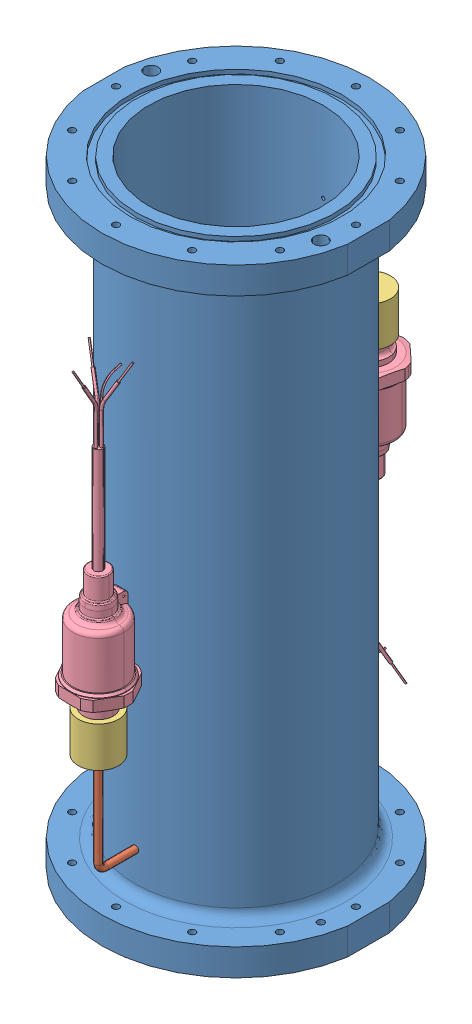
SolidWorks assembly ChamberAssembly, configuration Default. Lengths in mm.
Overall size (125.41 292.1 161.18).
7 component instances, 4 part files, 14 mates.
Components (placement in the parent):
- Aluminum Combustion Chamber-1: Aluminum Combustion Chamber [Default] at (131.1669 66.358 271.0107) size (125.41 292.1 127)
- PressureTap-1: PressureTap [Default] at (131.1669 320.358 226.5607) x (0 -1 0) z (1 0 0) size (52.39 20.64 3.17)
- PressureTap Adapter-1: PressureTap Adapter [Default] at (131.1669 272.733 207.5107) x (-0.372315 0 0.928106) z (0 -1 0) size (19.05 19.05 19.05)
- SPT25-20-1000A.step-1: SPT25-20-1000A.step [Default] at (131.1669 239.2659 207.5107) x (0.957502 0 -0.288425) z (0 1 0) size (29 29.01 153.3)
- PressureTap-2: PressureTap [Default] at (131.1669 98.108 317.0482) x (0 1 0) z (1 0 0) size (52.39 20.64 3.17)
- SPT25-20-1000A.step-2: SPT25-20-1000A.step [Default] at (131.1669 179.2001 336.0982) x (-1 0 -0.000826) z (0 -1 0) size (29 29.01 153.3)
- PressureTap Adapter-2: PressureTap Adapter [Default] at (131.1669 145.733 336.0982) x (-0.087486 0 -0.996166) z (0 1 0) size (19.05 19.05 19.05)
Mates (geometry in assembly coordinates):
- Parallel1: parallel: plane of PressureTap-1 through (131.1669 269.558 207.5107) normal (0 -1 0); plane of assembly through (0 0 0) normal (0 1 0)
- Concentric2: concentric: cylinder of PressureTap-1 through (131.1669 317.183 207.5107) axis (0 -1 0) radius 1.5875; cylinder of SPT25-20-1000A.step-1 through (131.1669 250.5159 207.5107) axis (0 -1 0) radius 7
- Concentric3: concentric: cylinder of Aluminum Combustion Chamber-1 through (131.1669 320.358 223.3857) axis (0 0 -1) radius 1.5875; cylinder of PressureTap-1 through (131.1669 320.358 226.5607) axis (0 0 -1) radius 1.5875
- Coincident1: coincident: plane of Aluminum Combustion Chamber-1 through (131.9606 320.358 226.5607) normal (0 0 -1); plane of PressureTap-1 through (131.1669 320.358 226.5607) normal (0 0 1)
- Concentric4: concentric: cylinder of Aluminum Combustion Chamber-1 through (131.1669 98.108 318.6357) axis (0 0 1) radius 1.5875; circle of PressureTap-2
- Parallel3: parallel: plane of Aluminum Combustion Chamber-1 through (131.1669 79.058 271.0107) normal (0 1 0); plane of PressureTap-2 through (131.1669 148.908 336.0982) normal (0 1 0)
- Coincident3: coincident: plane of Aluminum Combustion Chamber-1 through (131.5638 98.108 317.0482) normal (0 0 1); plane of PressureTap-2 through (131.1669 98.108 317.0482) normal (0 0 -1)
- Concentric5: concentric: cylinder of PressureTap-2 through (131.1669 101.283 336.0982) axis (0 1 0) radius 1.5875; cylinder of SPT25-20-1000A.step-2 through (131.1669 221.9501 336.0982) axis (0 -1 0) radius 5
- Concentric6: concentric: cylinder of SPT25-20-1000A.step-1 through (131.1669 250.5159 207.5107) axis (0 -1 0) radius 7; cone of PressureTap Adapter-1 through (131.1669 253.683 207.5107) axis (0 1 0)
- Coincident4: coincident: plane of PressureTap-1 through (131.1669 269.558 207.5107) normal (0 -1 0); plane of PressureTap Adapter-1 through (131.0191 269.558 207.879) normal (0 1 0)
- Concentric7: concentric: circle of PressureTap-2; cylinder of PressureTap Adapter-2 through (131.1669 145.733 336.0982) axis (0 -1 0) radius 1.5875
- Coincident5: coincident: plane of PressureTap-2 through (131.1669 148.908 336.0982) normal (0 1 0); plane of PressureTap Adapter-2 through (131.1322 148.908 335.7028) normal (0 -1 0)
- Coincident6: coincident: cone of SPT25-20-1000A.step-2 through (131.1669 156.2001 336.0982) axis (0 -1 0); circle of PressureTap Adapter-2
- Coincident7: coincident: circle of PressureTap Adapter-1; cone of SPT25-20-1000A.step-1 through (131.1669 262.2659 207.5107) axis (0 1 0)
